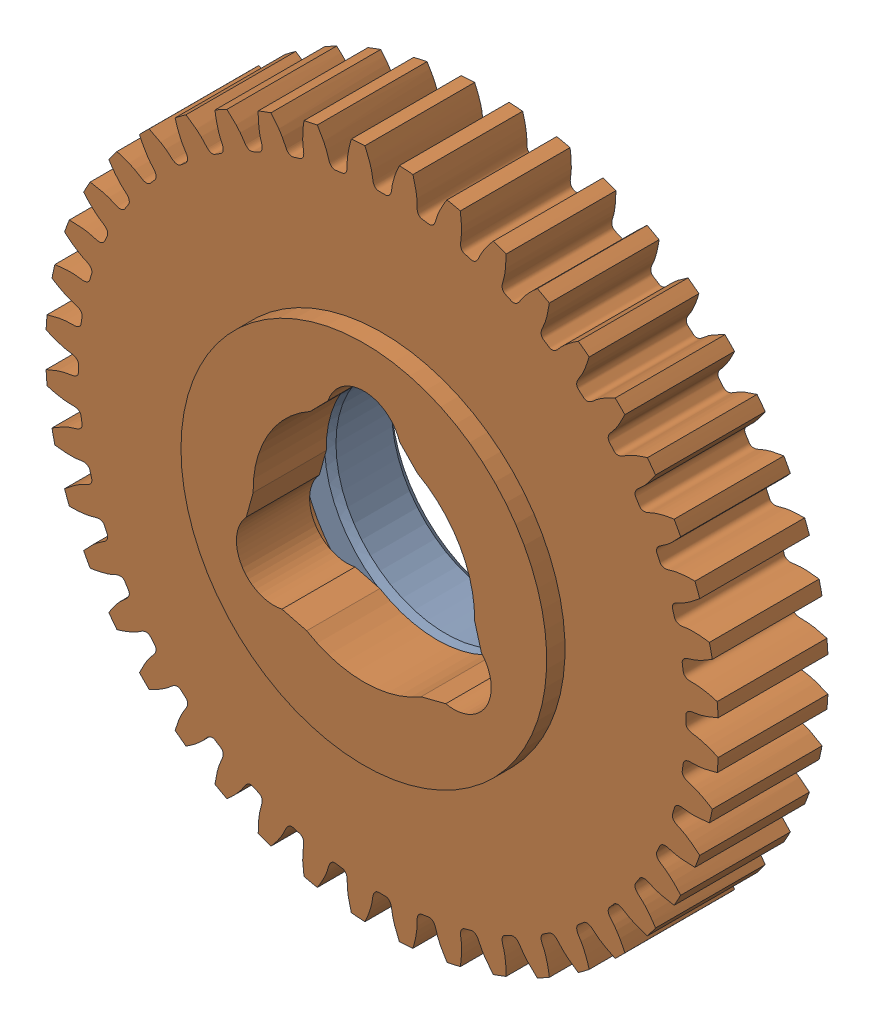
SolidWorks assembly 217-2709-101 Rev1, configuration Default. Lengths in mm.
Overall size (58.74 58.74 12.7).
2 component instances, 2 part files, 0 mates.
Components (placement in the parent):
- 217-2428-022 Rev1-1: 217-2428-022 Rev1 [Default] at origin size (28.57 28.57 6.1)
- 217-2709-001_44t Steel-1: 217-2709-001_44t Steel [Default] at (0 0 3.302) size (58.74 58.74 11.11)
